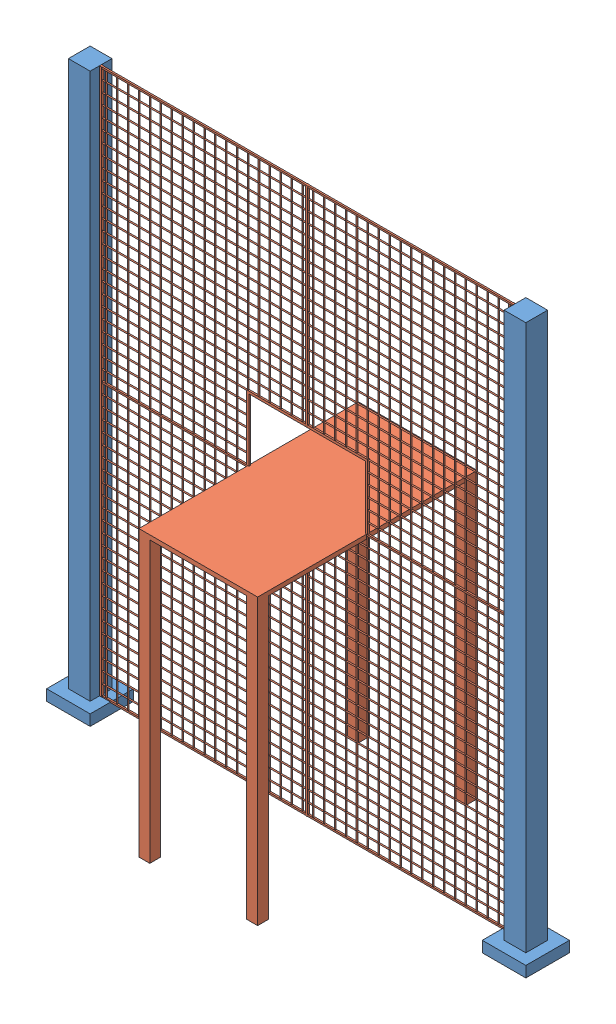
SolidWorks assembly bariera_2m - porta, configuration Default. Lengths in mm.
Overall size (2200 2556.25 1007.5).
3 component instances, 2 part files, 7 mates.
Components (placement in the parent):
- palo_barriera-1: palo_barriera [Default] at origin size (200 2555 200)
- palo_barriera-2: palo_barriera [Default] at (2000 0 0) size (200 2555 200)
- rete_2m-porta-1: rete_2m-porta [Default] at (77.5 2551.25 2.5) x (1 0 0) z (0 -1 0) size (1900 1007.5 2556.25)
Mates (geometry in assembly coordinates):
- Coincidente1: coordinate: point of palo_barriera-1
- Coincidente4: coincident anti-aligned: plane of palo_barriera-1 through (50 2550 -50) normal (1 0 0); plane of rete_2m-porta-1 through (50 2551.25 2.5) normal (-1 0 0)
- Distanza2: distance = 50 mm: cylinder of rete_2m-porta-1 through (77.5 51.25 2.5) axis (0 1 0) radius 2.5; plane of palo_barriera-1 through (-50 2550 50) normal (0 0 1)
- Coincidente9: coincident aligned: plane of palo_barriera-1 through (-50 2550 50) normal (0 0 1); plane of palo_barriera-2 through (1950 2550 50) normal (0 0 1)
- Coincidente10: coincident aligned: plane of palo_barriera-1 through (0 2555 0) normal (0 1 0); plane of palo_barriera-2 through (2000 2555 0) normal (0 1 0)
- Coincidente13: coincident anti-aligned: plane of palo_barriera-2 through (1950 2550 -50) normal (-1 0 0); plane of rete_2m-porta-1 through (1950 2551.25 2.5) normal (1 0 0)
- Coincidente14: coincident aligned: plane of palo_barriera-1 through (0 2555 0) normal (0 1 0); plane of rete_2m-porta-1 through (1960.6066 2555 6.25) normal (0 1 0)
